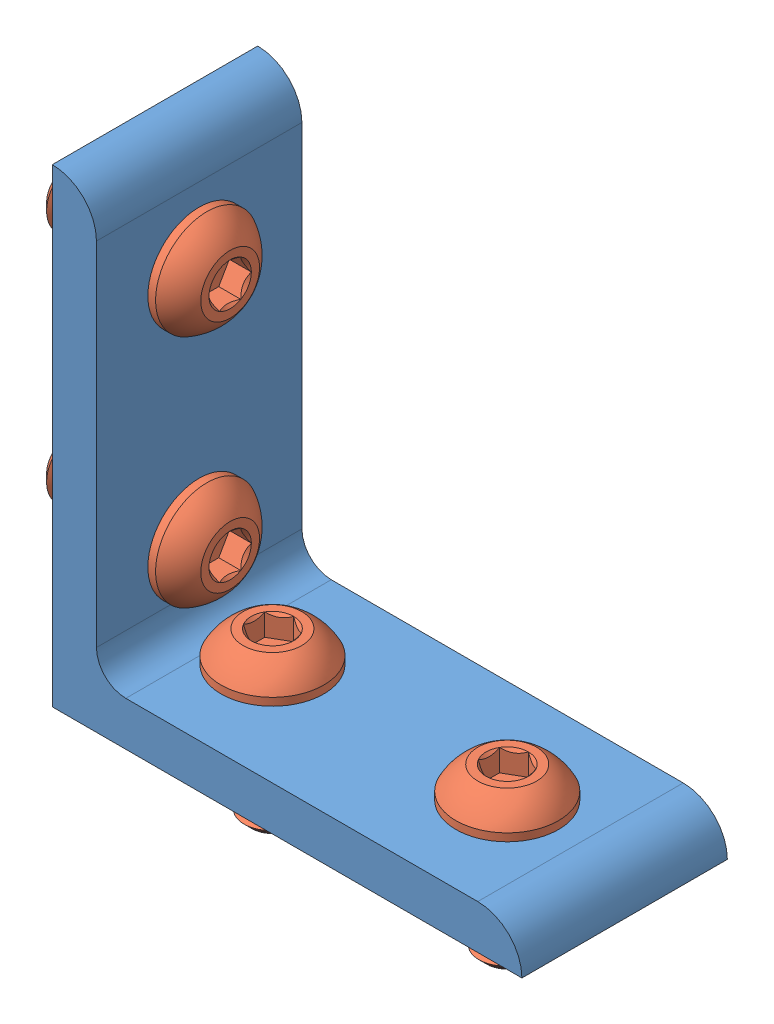
SolidWorks assembly CornerBracketWBolts, configuration Default. Lengths in mm.
Overall size (60.74 60.74 22.23).
5 component instances, 2 part files, 8 mates.
Components (placement in the parent):
- 47065T239_ALUMINUM T-SLOTTED FRAMING EXTRUSION-1: 47065T239_ALUMINUM T-SLOTTED FRAMING EXTRUSION [47065T239] at (-19.4251 3.4504 44.2567) size (50.8 50.8 22.23)
- Bolt 47065T226_ALUMINUM T-SLOTTED FRAMING EXTRUSION-1: Bolt 47065T226_ALUMINUM T-SLOTTED FRAMING EXTRUSION [47065T226] at (18.6749 8.2256 44.2567) size (11.1 18.3 11.1)
- Bolt 47065T226_ALUMINUM T-SLOTTED FRAMING EXTRUSION-2: Bolt 47065T226_ALUMINUM T-SLOTTED FRAMING EXTRUSION [47065T226] at (-6.7251 8.2256 44.2567) size (11.1 18.3 11.1)
- Bolt 47065T226_ALUMINUM T-SLOTTED FRAMING EXTRUSION-3: Bolt 47065T226_ALUMINUM T-SLOTTED FRAMING EXTRUSION [47065T226] at (-14.6499 16.1504 44.2567) x (0 -1 0) z (0 0 1) size (11.1 18.3 11.1)
- Bolt 47065T226_ALUMINUM T-SLOTTED FRAMING EXTRUSION-4: Bolt 47065T226_ALUMINUM T-SLOTTED FRAMING EXTRUSION [47065T226] at (-14.6499 41.5504 44.2567) x (0 -1 0) z (0 0 1) size (11.1 18.3 11.1)
Mates (geometry in assembly coordinates):
- Coincident1: coincident anti-aligned: plane of 47065T239_ALUMINUM T-SLOTTED FRAMING EXTRUSION-1 through (-11.4749 8.2256 55.3692) normal (0 1 0); plane of Bolt 47065T226_ALUMINUM T-SLOTTED FRAMING EXTRUSION-1 through (24.2248 8.2256 44.2567) normal (0 -1 0)
- Concentric1: concentric aligned: circle of 47065T239_ALUMINUM T-SLOTTED FRAMING EXTRUSION-1; circle of Bolt 47065T226_ALUMINUM T-SLOTTED FRAMING EXTRUSION-1
- Coincident2: coincident anti-aligned: plane of 47065T239_ALUMINUM T-SLOTTED FRAMING EXTRUSION-1 through (-11.4749 8.2256 55.3692) normal (0 1 0); plane of Bolt 47065T226_ALUMINUM T-SLOTTED FRAMING EXTRUSION-2 through (-1.1752 8.2256 44.2567) normal (0 -1 0)
- Concentric2: concentric aligned: circle of 47065T239_ALUMINUM T-SLOTTED FRAMING EXTRUSION-1; circle of Bolt 47065T226_ALUMINUM T-SLOTTED FRAMING EXTRUSION-2
- Coincident3: coincident anti-aligned: plane of 47065T239_ALUMINUM T-SLOTTED FRAMING EXTRUSION-1 through (-14.6499 49.4752 55.3692) normal (1 0 0); plane of Bolt 47065T226_ALUMINUM T-SLOTTED FRAMING EXTRUSION-3 through (-14.6499 10.6005 44.2567) normal (-1 0 0)
- Concentric3: concentric aligned: circle of 47065T239_ALUMINUM T-SLOTTED FRAMING EXTRUSION-1; circle of Bolt 47065T226_ALUMINUM T-SLOTTED FRAMING EXTRUSION-3
- Coincident4: coincident anti-aligned: plane of 47065T239_ALUMINUM T-SLOTTED FRAMING EXTRUSION-1 through (-14.6499 49.4752 55.3692) normal (1 0 0); plane of Bolt 47065T226_ALUMINUM T-SLOTTED FRAMING EXTRUSION-4 through (-14.6499 36.0005 44.2567) normal (-1 0 0)
- Concentric4: concentric aligned: circle of 47065T239_ALUMINUM T-SLOTTED FRAMING EXTRUSION-1; circle of Bolt 47065T226_ALUMINUM T-SLOTTED FRAMING EXTRUSION-4
